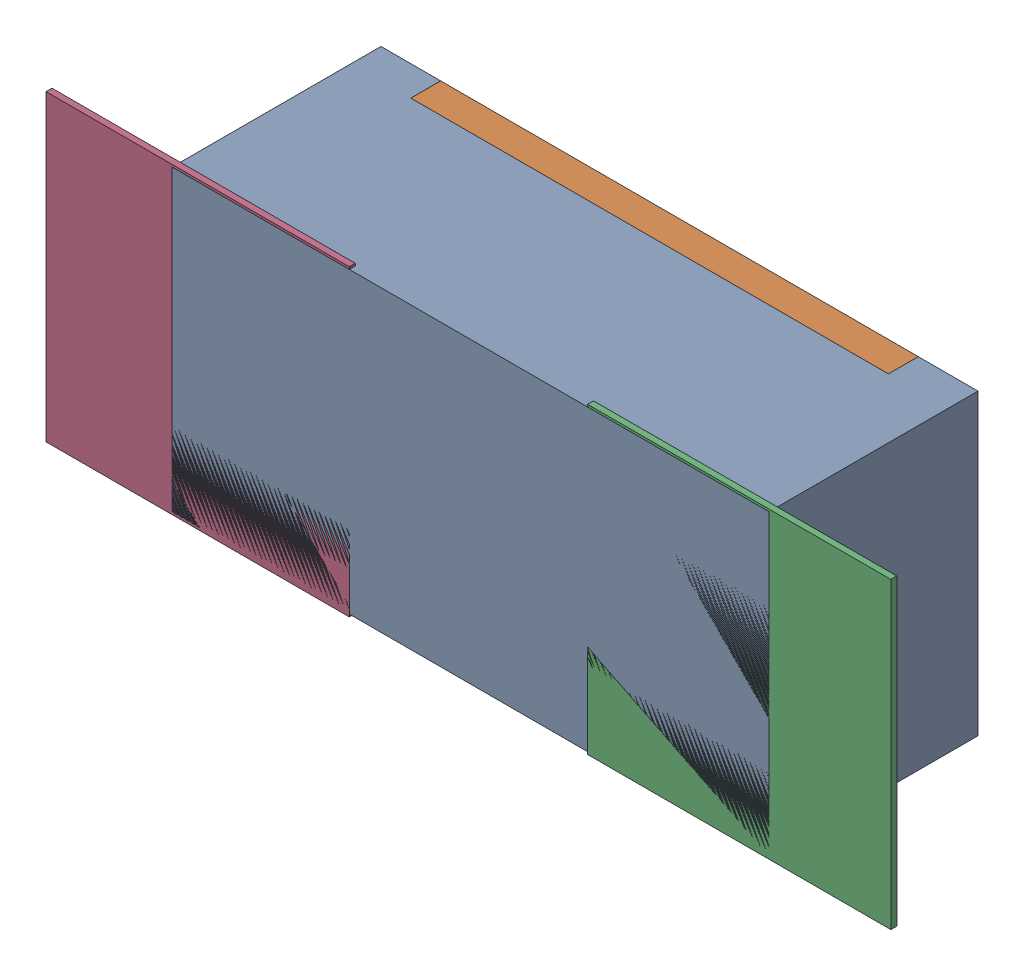
SolidWorks assembly R163, configuration Défaut. Lengths in mm.
Overall size (1.42 0.51 0.35).
5 component instances, 2 part files, 0 mates.
Components (placement in the parent):
- R0402-1: R0402 [Défaut] at (13.4366 -1.7145 -2.0818) x (1 0 0) z (0 0 -1) size (1 0.5 0.35)
- 6504207776-1: 6504207776 [Défaut] at (13.8866 -1.7146 -2.0918) size (0.51 0.51 0.01)
  - Extruded-1: Extruded [Défaut] at origin size (0.51 0.51 0.01)
- 6504207776-2: 6504207776 [Défaut] at (12.9795 -1.7146 -2.0918) size (0.51 0.51 0.01)
  - Extruded-1: Extruded [Défaut] at origin size (0.51 0.51 0.01)
